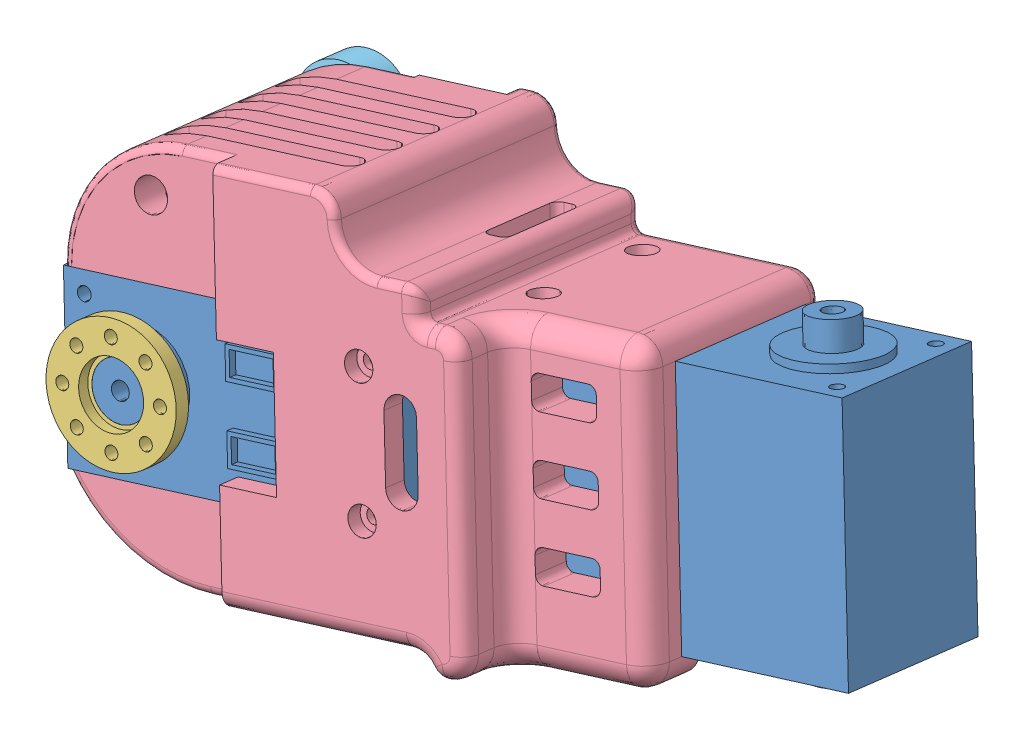
SolidWorks assembly link8, configuration ﾃﾞﾌｫﾙﾄ. Lengths in mm.
Overall size (99.23 67.37 55.33).
6 component instances, 5 part files, 10 mates.
Components (placement in the parent):
- KRS2572HV-3: KRS2572HV [ﾃﾞﾌｫﾙﾄ] at (-73.4245 38.8845 136.6494) x (0.968907 0.190479 -0.157912) z (-0.219094 0.95705 -0.189877) size (41 21 38)
- KRS2572HV-4: KRS2572HV [ﾃﾞﾌｫﾙﾄ] at (-80.7116 48.8148 145.0778) x (-0.968907 -0.190479 0.157912) z (-0.114962 -0.218571 -0.969026) size (41 21 38)
- SmallHornB-4: SmallHornB [ﾃﾞﾌｫﾙﾄ] at (-117.6729 45.8179 117.3222) x (0.528861 0.812287 -0.24596) z (-0.114962 -0.218571 -0.969026) size (16 16 4.2)
- SmallFreeHornC-2: SmallFreeHornC [ﾃﾞﾌｫﾙﾄ] at (-113.4998 53.752 152.4979) x (-0.973145 -0.171059 0.154035) z (-0.114962 -0.218571 -0.969026) size (16 16 3.5)
- Base-1: Base [ﾃﾞﾌｫﾙﾄ] at (-77.292 34.0088 116.5368) x (0.968907 0.190479 -0.157912) z (-0.114962 -0.218571 -0.969026) size (68.1 48.5 36.5)
- thrustBearing^link8-1: thrustBearing^link8 [ﾃﾞﾌｫﾙﾄ] at (-86.2052 33.1376 117.7907) x (0.968907 0.190479 -0.157912) z (-0.114962 -0.218571 -0.969026) size (11 11 4.5) (virtual)
Mates (geometry in assembly coordinates):
- 同心円26: concentric aligned: circle of KRS2572HV-4; circle of SmallHornB-4
- 一致29: coincident anti-aligned: plane of KRS2572HV-4 through (-118.0408 45.1185 114.2214) normal (-0.114962 -0.218571 -0.969026); plane of SmallHornB-4 through (-118.0408 45.1185 114.2214) normal (0.114962 0.218571 0.969026)
- 同心円27: concentric aligned: circle of KRS2572HV-4; circle of SmallFreeHornC-2
- 一致31: coincident anti-aligned: plane of KRS2572HV-4 through (-113.9022 52.987 149.1063) normal (0.114962 0.218571 0.969026); plane of SmallFreeHornC-2 through (-113.9022 52.987 149.1063) normal (-0.114962 -0.218571 -0.969026)
- Concentric4: concentric anti-aligned: circle of KRS2572HV-3; circle of Base-1
- Concentric5: concentric anti-aligned: circle of KRS2572HV-3; circle of Base-1
- Symmetric1: symmetric anti-aligned: plane of KRS2572HV-3 through (-80.1068 68.0745 130.8582) normal (-0.219094 0.95705 -0.189877); plane of Base-1 through (-104.6907 65.1032 144.2486) normal (0.219094 -0.95705 0.189877); plane of Base-1 through (-101.75 28.1125 117.6724) normal (-0.114962 -0.218571 -0.969026)
- Concentric7: concentric anti-aligned: circle of KRS2572HV-4; circle of Base-1
- Concentric8: concentric anti-aligned: circle of KRS2572HV-4; circle of Base-1
- Coincident4: coincident anti-aligned: plane of KRS2572HV-4 through (-80.7116 48.8148 145.0778) normal (0.114962 0.218571 0.969026); plane of Base-1 through (-100.0898 45.0052 148.236) normal (-0.114962 -0.218571 -0.969026)
